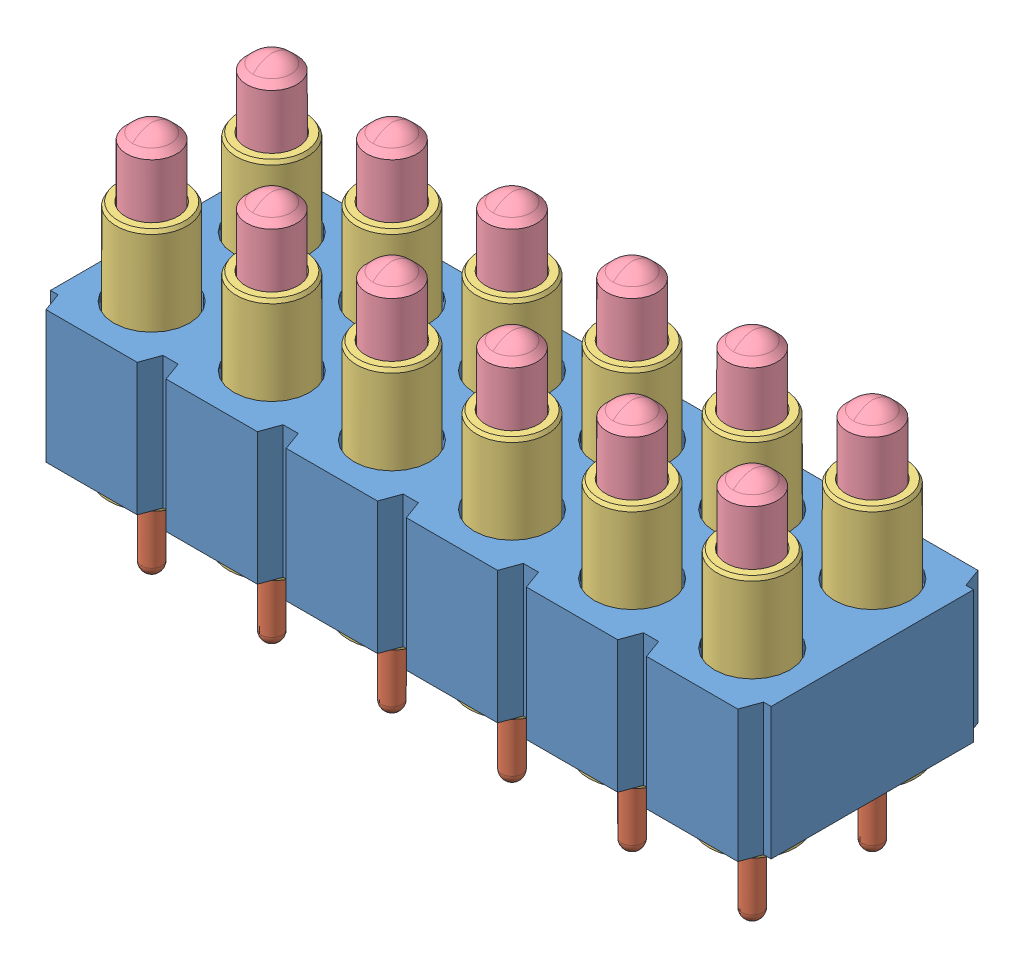
SolidWorks assembly mill-max-818-22-012-10-000101, configuration Default. Lengths in mm.
Overall size (15.24 8.23 5.08).
49 component instances, 5 part files, 0 mates.
Components (placement in the parent):
- mill-max-818-22-012-10-000101_P4XX-28-010-00-090000-1: mill-max-818-22-012-10-000101_P4XX-28-010-00-090000 [Default] at origin size (15.24 2.79 5.08)
- mill-max-818-22-012-10-000101_0963-0-1: mill-max-818-22-012-10-000101_0963-0 [Default] at (0.9644 -4.953 -1.27) x (0 1 0) z (0 0 1) size (4.04 1.31 1.31)
- mill-max-818-22-012-10-000101_0954-0-1: mill-max-818-22-012-10-000101_0954-0 [Default] at (0.9644 -3.2004 -1.27) x (0 1 0) z (-0.856247 0 0.516567) size (5.03 1.83 1.83)
- mill-max-818-22-012-10-000101_0918-X-1: mill-max-818-22-012-10-000101_0918-X [Default] at (0.9644 -1.2192 -1.27) x (0 1 0) z (0 0 1) size (4.5 1.25 1.25)
- mill-max-818-22-012-10-000101_6875-0-00-00-75-XX-43-0C-1: mill-max-818-22-012-10-000101_6875-0-00-00-75-XX-43-0C [Default] at (0.9644 0.6355 -1.27) x (-0.956034 0 -0.293257) z (0 -1 0) size (0.2 0.07 3.45)
- mill-max-818-22-012-10-000101_0963-0-2: mill-max-818-22-012-10-000101_0963-0 [Default] at (0.9644 -4.953 -3.81) x (0 1 0) z (0 0 1) size (4.04 1.31 1.31)
- mill-max-818-22-012-10-000101_0954-0-2: mill-max-818-22-012-10-000101_0954-0 [Default] at (0.9644 -3.2004 -3.81) x (0 1 0) z (0.135119 0 0.990829) size (5.03 1.83 1.83)
- mill-max-818-22-012-10-000101_0918-X-2: mill-max-818-22-012-10-000101_0918-X [Default] at (0.9644 -1.2192 -3.81) x (0 1 0) z (0.012366 0 0.999924) size (4.5 1.25 1.25)
- mill-max-818-22-012-10-000101_6875-0-00-00-75-XX-43-0C-2: mill-max-818-22-012-10-000101_6875-0-00-00-75-XX-43-0C [Default] at (0.9644 0.6358 -1.27) x (-0.954499 0 -0.298214) z (0 -1 0) size (0.2 0.07 3.45)
- mill-max-818-22-012-10-000101_6875-0-00-00-75-XX-43-0C-3: mill-max-818-22-012-10-000101_6875-0-00-00-75-XX-43-0C [Default] at (3.5044 0.6358 -1.27) x (-0.954499 0 -0.298214) z (0 -1 0) size (0.2 0.07 3.45)
- mill-max-818-22-012-10-000101_0918-X-3: mill-max-818-22-012-10-000101_0918-X [Default] at (3.5044 -1.2192 -3.81) x (0 1 0) z (0.012366 0 0.999924) size (4.5 1.25 1.25)
- mill-max-818-22-012-10-000101_0954-0-3: mill-max-818-22-012-10-000101_0954-0 [Default] at (3.5044 -3.2004 -3.81) x (0 1 0) z (0.135119 0 0.990829) size (5.03 1.83 1.83)
- mill-max-818-22-012-10-000101_0963-0-3: mill-max-818-22-012-10-000101_0963-0 [Default] at (3.5044 -4.953 -3.81) x (0 1 0) z (0 0 1) size (4.04 1.31 1.31)
- mill-max-818-22-012-10-000101_6875-0-00-00-75-XX-43-0C-4: mill-max-818-22-012-10-000101_6875-0-00-00-75-XX-43-0C [Default] at (3.5044 0.6355 -1.27) x (-0.956034 0 -0.293257) z (0 -1 0) size (0.2 0.07 3.45)
- mill-max-818-22-012-10-000101_0918-X-4: mill-max-818-22-012-10-000101_0918-X [Default] at (3.5044 -1.2192 -1.27) x (0 1 0) z (0 0 1) size (4.5 1.25 1.25)
- mill-max-818-22-012-10-000101_0954-0-4: mill-max-818-22-012-10-000101_0954-0 [Default] at (3.5044 -3.2004 -1.27) x (0 1 0) z (-0.856247 0 0.516567) size (5.03 1.83 1.83)
- mill-max-818-22-012-10-000101_0963-0-4: mill-max-818-22-012-10-000101_0963-0 [Default] at (3.5044 -4.953 -1.27) x (0 1 0) z (0 0 1) size (4.04 1.31 1.31)
- mill-max-818-22-012-10-000101_6875-0-00-00-75-XX-43-0C-5: mill-max-818-22-012-10-000101_6875-0-00-00-75-XX-43-0C [Default] at (6.0444 0.6358 -1.27) x (-0.954499 0 -0.298214) z (0 -1 0) size (0.2 0.07 3.45)
- mill-max-818-22-012-10-000101_6875-0-00-00-75-XX-43-0C-6: mill-max-818-22-012-10-000101_6875-0-00-00-75-XX-43-0C [Default] at (8.5844 0.6358 -1.27) x (-0.954499 0 -0.298214) z (0 -1 0) size (0.2 0.07 3.45)
- mill-max-818-22-012-10-000101_6875-0-00-00-75-XX-43-0C-7: mill-max-818-22-012-10-000101_6875-0-00-00-75-XX-43-0C [Default] at (11.1244 0.6358 -1.27) x (-0.954499 0 -0.298214) z (0 -1 0) size (0.2 0.07 3.45)
- mill-max-818-22-012-10-000101_6875-0-00-00-75-XX-43-0C-8: mill-max-818-22-012-10-000101_6875-0-00-00-75-XX-43-0C [Default] at (13.6644 0.6358 -1.27) x (-0.954499 0 -0.298214) z (0 -1 0) size (0.2 0.07 3.45)
- mill-max-818-22-012-10-000101_0918-X-5: mill-max-818-22-012-10-000101_0918-X [Default] at (6.0444 -1.2192 -3.81) x (0 1 0) z (0.012366 0 0.999924) size (4.5 1.25 1.25)
- mill-max-818-22-012-10-000101_0918-X-6: mill-max-818-22-012-10-000101_0918-X [Default] at (8.5844 -1.2192 -3.81) x (0 1 0) z (0.012366 0 0.999924) size (4.5 1.25 1.25)
- mill-max-818-22-012-10-000101_0918-X-7: mill-max-818-22-012-10-000101_0918-X [Default] at (11.1244 -1.2192 -3.81) x (0 1 0) z (0.012366 0 0.999924) size (4.5 1.25 1.25)
- mill-max-818-22-012-10-000101_0918-X-8: mill-max-818-22-012-10-000101_0918-X [Default] at (13.6644 -1.2192 -3.81) x (0 1 0) z (0.012366 0 0.999924) size (4.5 1.25 1.25)
- mill-max-818-22-012-10-000101_0954-0-5: mill-max-818-22-012-10-000101_0954-0 [Default] at (6.0444 -3.2004 -3.81) x (0 1 0) z (0.135119 0 0.990829) size (5.03 1.83 1.83)
- mill-max-818-22-012-10-000101_0954-0-6: mill-max-818-22-012-10-000101_0954-0 [Default] at (8.5844 -3.2004 -3.81) x (0 1 0) z (0.135119 0 0.990829) size (5.03 1.83 1.83)
- mill-max-818-22-012-10-000101_0954-0-7: mill-max-818-22-012-10-000101_0954-0 [Default] at (11.1244 -3.2004 -3.81) x (0 1 0) z (0.135119 0 0.990829) size (5.03 1.83 1.83)
- mill-max-818-22-012-10-000101_0954-0-8: mill-max-818-22-012-10-000101_0954-0 [Default] at (13.6644 -3.2004 -3.81) x (0 1 0) z (0.135119 0 0.990829) size (5.03 1.83 1.83)
- mill-max-818-22-012-10-000101_0963-0-5: mill-max-818-22-012-10-000101_0963-0 [Default] at (6.0444 -4.953 -3.81) x (0 1 0) z (0 0 1) size (4.04 1.31 1.31)
- mill-max-818-22-012-10-000101_0963-0-6: mill-max-818-22-012-10-000101_0963-0 [Default] at (8.5844 -4.953 -3.81) x (0 1 0) z (0 0 1) size (4.04 1.31 1.31)
- mill-max-818-22-012-10-000101_0963-0-7: mill-max-818-22-012-10-000101_0963-0 [Default] at (11.1244 -4.953 -3.81) x (0 1 0) z (0 0 1) size (4.04 1.31 1.31)
- mill-max-818-22-012-10-000101_0963-0-8: mill-max-818-22-012-10-000101_0963-0 [Default] at (13.6644 -4.953 -3.81) x (0 1 0) z (0 0 1) size (4.04 1.31 1.31)
- mill-max-818-22-012-10-000101_6875-0-00-00-75-XX-43-0C-9: mill-max-818-22-012-10-000101_6875-0-00-00-75-XX-43-0C [Default] at (6.0444 0.6355 -1.27) x (-0.956034 0 -0.293257) z (0 -1 0) size (0.2 0.07 3.45)
- mill-max-818-22-012-10-000101_6875-0-00-00-75-XX-43-0C-10: mill-max-818-22-012-10-000101_6875-0-00-00-75-XX-43-0C [Default] at (8.5844 0.6355 -1.27) x (-0.956034 0 -0.293257) z (0 -1 0) size (0.2 0.07 3.45)
- mill-max-818-22-012-10-000101_6875-0-00-00-75-XX-43-0C-11: mill-max-818-22-012-10-000101_6875-0-00-00-75-XX-43-0C [Default] at (11.1244 0.6355 -1.27) x (-0.956034 0 -0.293257) z (0 -1 0) size (0.2 0.07 3.45)
- mill-max-818-22-012-10-000101_6875-0-00-00-75-XX-43-0C-12: mill-max-818-22-012-10-000101_6875-0-00-00-75-XX-43-0C [Default] at (13.6644 0.6355 -1.27) x (-0.956034 0 -0.293257) z (0 -1 0) size (0.2 0.07 3.45)
- mill-max-818-22-012-10-000101_0918-X-9: mill-max-818-22-012-10-000101_0918-X [Default] at (6.0444 -1.2192 -1.27) x (0 1 0) z (0 0 1) size (4.5 1.25 1.25)
- mill-max-818-22-012-10-000101_0918-X-10: mill-max-818-22-012-10-000101_0918-X [Default] at (8.5844 -1.2192 -1.27) x (0 1 0) z (0 0 1) size (4.5 1.25 1.25)
- mill-max-818-22-012-10-000101_0918-X-11: mill-max-818-22-012-10-000101_0918-X [Default] at (11.1244 -1.2192 -1.27) x (0 1 0) z (0 0 1) size (4.5 1.25 1.25)
- mill-max-818-22-012-10-000101_0918-X-12: mill-max-818-22-012-10-000101_0918-X [Default] at (13.6644 -1.2192 -1.27) x (0 1 0) z (0 0 1) size (4.5 1.25 1.25)
- mill-max-818-22-012-10-000101_0954-0-9: mill-max-818-22-012-10-000101_0954-0 [Default] at (6.0444 -3.2004 -1.27) x (0 1 0) z (-0.856247 0 0.516567) size (5.03 1.83 1.83)
- mill-max-818-22-012-10-000101_0954-0-10: mill-max-818-22-012-10-000101_0954-0 [Default] at (8.5844 -3.2004 -1.27) x (0 1 0) z (-0.856247 0 0.516567) size (5.03 1.83 1.83)
- mill-max-818-22-012-10-000101_0954-0-11: mill-max-818-22-012-10-000101_0954-0 [Default] at (11.1244 -3.2004 -1.27) x (0 1 0) z (-0.856247 0 0.516567) size (5.03 1.83 1.83)
- mill-max-818-22-012-10-000101_0954-0-12: mill-max-818-22-012-10-000101_0954-0 [Default] at (13.6644 -3.2004 -1.27) x (0 1 0) z (-0.856247 0 0.516567) size (5.03 1.83 1.83)
- mill-max-818-22-012-10-000101_0963-0-9: mill-max-818-22-012-10-000101_0963-0 [Default] at (6.0444 -4.953 -1.27) x (0 1 0) z (0 0 1) size (4.04 1.31 1.31)
- mill-max-818-22-012-10-000101_0963-0-10: mill-max-818-22-012-10-000101_0963-0 [Default] at (8.5844 -4.953 -1.27) x (0 1 0) z (0 0 1) size (4.04 1.31 1.31)
- mill-max-818-22-012-10-000101_0963-0-11: mill-max-818-22-012-10-000101_0963-0 [Default] at (11.1244 -4.953 -1.27) x (0 1 0) z (0 0 1) size (4.04 1.31 1.31)
- mill-max-818-22-012-10-000101_0963-0-12: mill-max-818-22-012-10-000101_0963-0 [Default] at (13.6644 -4.953 -1.27) x (0 1 0) z (0 0 1) size (4.04 1.31 1.31)
